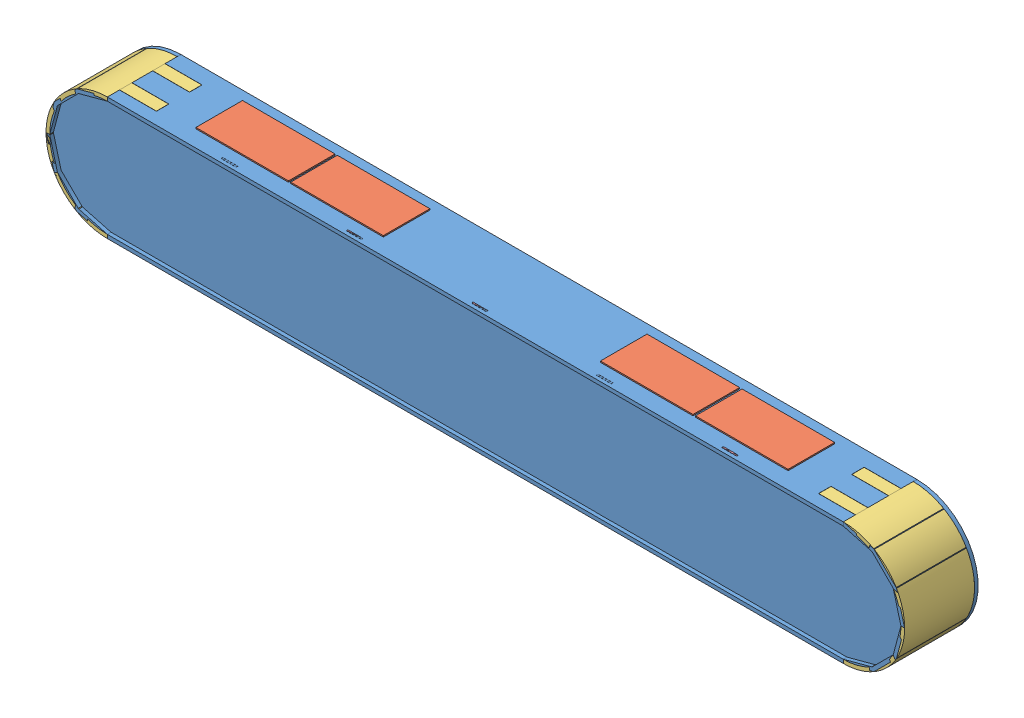
SolidWorks assembly Assem3, configuration Default. Lengths in mm.
Overall size (700 101 60).
10 component instances, 4 part files, 3 mates.
Components (placement in the parent):
- Assem2-1: Assem2 [Default] at (-46.9101 -28.8986 44.0474) size (700 101 60)
  - Assem1-1: Assem1 [Default] at (410.585 333.6547 480.0278) size (700 100 60)
    - partFull-1: partFull [Default] at (-199.8938 48.0418 42.8423) size (700 100 60)
  - ustKapaklar8-1: ustKapaklar8 [Default] at (-41.9088 381.6965 522.7702) size (75.5 2 38)
  - ustKapaklar8-2: ustKapaklar8 [Default] at (288.0912 381.6965 522.7702) size (75.5 2 38)
  - ustKapaklar8-3: ustKapaklar8 [Default] at (-119.2088 381.6965 522.7702) size (75.5 2 38)
  - ustKapaklar8-4: ustKapaklar8 [Default] at (210.5912 381.6965 522.7702) size (75.5 2 38)
  - yanKapaklar4-1: yanKapaklar4 [Default] at (210.6912 381.6965 522.8702) size (80 100 57)
  - yanKapaklar4-2: yanKapaklar4 [Default] at (210.6912 381.6965 522.8702) x (-1 0 0) z (0 0 1) size (80 100 57)
- plexiDisli-1: plexiDisli [Default] at (163.8811 352.7979 566.8175) size (694 100 1.2)
Mates (geometry in assembly coordinates):
- Coincident1: coincident: plane of Assem2-1/Assem1-1/partFull-1 through (-136.2189 305.7979 569.9175) normal (0 1 0); plane of plexiDisli-1 through (-142.9391 305.7979 622.6175) normal (0 -1 0)
- Coincident2: coincident: plane of Assem2-1/Assem1-1/partFull-1 through (259.7811 302.7979 622.6175) normal (0 0 1); plane of plexiDisli-1 through (-142.9391 352.7979 622.6175) normal (0 0 -1)
- Coincident4: coincident anti-aligned: plane of Assem2-1/Assem1-1/partFull-1 through (67.8811 302.7979 622.7175) normal (-1 0 0); plane of plexiDisli-1 through (67.8811 302.7879 622.6175) normal (1 0 0)
